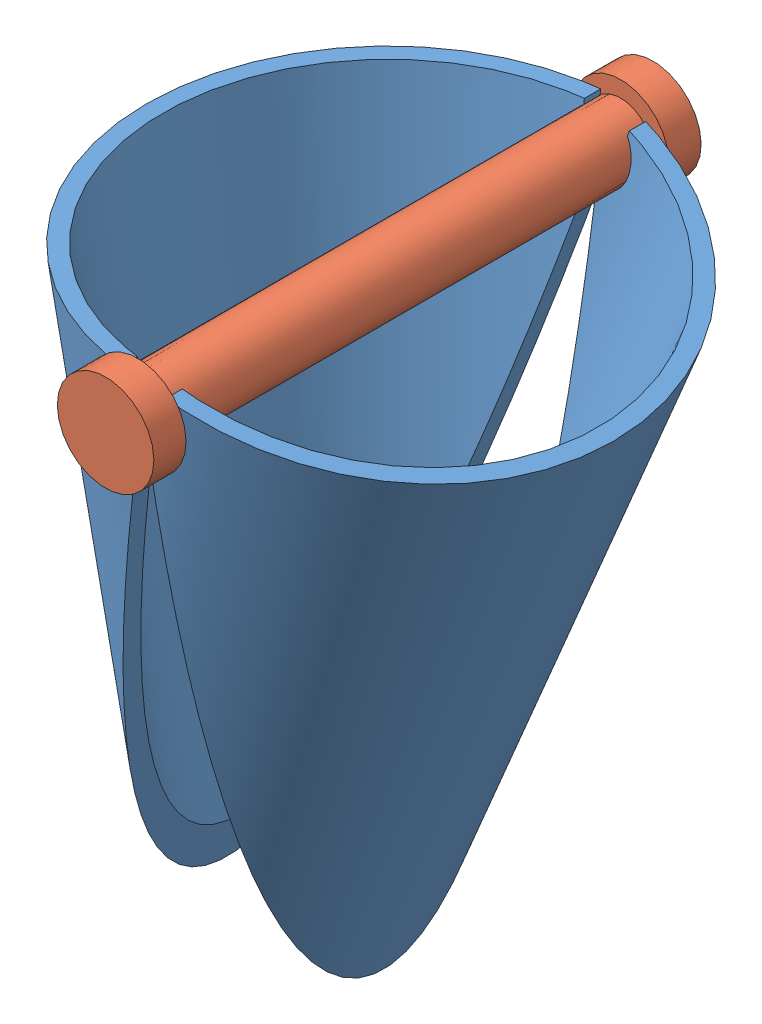
SolidWorks assembly Claw Design 1, configuration Default. Lengths in mm.
Overall size (92.1 135.63 107.95).
3 component instances, 2 part files, 4 mates.
Components (placement in the parent):
- Claw 3-1: Claw 3 [Default] at (-8.4595 20.3041 -9.3304) size (44.77 120.65 95.13)
- Claw 3-2: Claw 3 [Default] at (-10.114 20.5131 -9.3304) x (-0.968598 0.248633 0) z (0 0 -1) size (44.77 120.65 95.13)
- Claw Pin-1: Claw Pin [Default] at (-10.0755 14.1632 38.3973) x (0.578809 -0.815463 0) z (0 0 1) size (19.05 19.05 107.95)
Mates (geometry in assembly coordinates):
- Concentric1: concentric aligned: cylinder of Claw 3-1 through (-10.0755 14.1632 -56.9554) axis (0 0 1) radius 6.35; cylinder of Claw Pin-1 through (-10.0755 14.1632 -56.8527) axis (0 0 1) radius 6.35
- Concentric3: concentric anti-aligned: cylinder of Claw 3-2 through (-10.0755 14.1632 38.2946) axis (0 0 -1) radius 6.35; cylinder of Claw Pin-1 through (-10.0755 14.1632 -56.8527) axis (0 0 1) radius 6.35
- Distance1: distance = 0.1985 mm: plane of Claw Pin-1 through (-10.0755 14.1632 -56.8527) normal (0 0 1); point of Claw 3-2
- Distance2: distance = 0.1985 mm: point of Claw 3-1; plane of Claw Pin-1 through (-10.0755 14.1632 -56.8527) normal (0 0 1)
